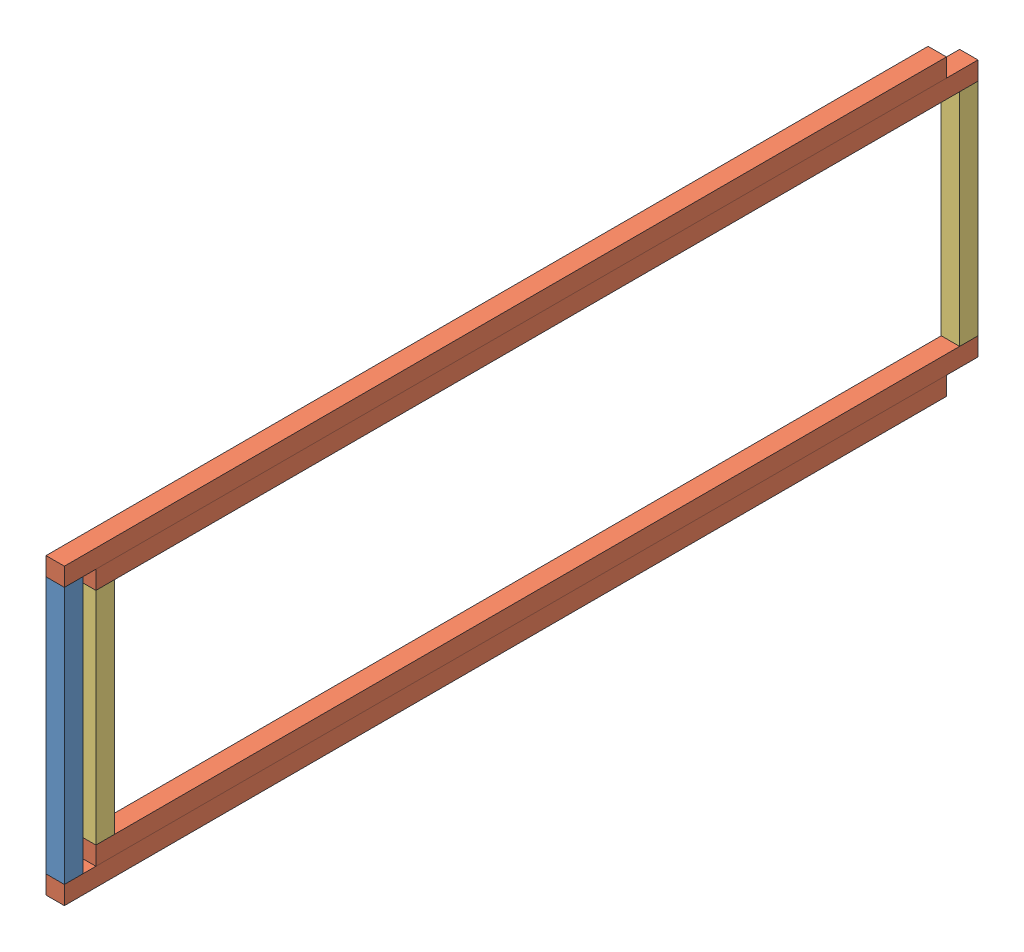
SolidWorks assembly Version 2.0 MAST, configuration Default. Lengths in mm.
Overall size (25.4 406.4 1262.78).
7 component instances, 3 part files, 17 mates.
Components (placement in the parent):
- Outisde Base-1: Outisde Base [Default] at (-217.3626 170.9905 454.9018) size (25.4 355.6 25.4)
- Outside long silder-1: Outside long silder [Default] at (-217.3626 -32.2095 -129.2982) x (1 0 0) z (0 1 0) size (25.4 1219.2 25.4)
- Outside long silder-2: Outside long silder [Default] at (-217.3626 348.7905 -129.2982) x (1 0 0) z (0 1 0) size (25.4 1219.2 25.4)
- inside Base-1: inside Base [Default] at (-217.3626 170.9905 411.3195) size (25.4 304.8 25.4)
- Outside long silder-3: Outside long silder [Default] at (-217.3626 -6.8095 -172.8805) x (1 0 0) z (0 1 0) size (25.4 1219.2 25.4)
- Outside long silder-4: Outside long silder [Default] at (-217.3626 323.3905 -172.8805) x (1 0 0) z (0 1 0) size (25.4 1219.2 25.4)
- inside Base-2: inside Base [Default] at (-217.3626 170.9905 -782.4805) size (25.4 304.8 25.4)
Mates (geometry in assembly coordinates):
- Coincident1: coincident aligned: plane of Outisde Base-1 through (-217.3626 170.9905 480.3018) normal (0 0 1); plane of Outside long silder-1 through (-230.0626 -6.8095 480.3018) normal (0 0 1)
- Coincident2: coincident aligned: plane of Outisde Base-1 through (-204.6626 -6.8095 480.3018) normal (1 0 0); plane of Outside long silder-1 through (-204.6626 -6.8095 480.3018) normal (1 0 0)
- Coincident3: coincident anti-aligned: plane of Outisde Base-1 through (-230.0626 -6.8095 480.3018) normal (0 -1 0); plane of Outside long silder-1 through (-217.3626 -6.8095 -129.2982) normal (0 1 0)
- Coincident5: coincident aligned: plane of Outisde Base-1 through (-217.3626 170.9905 480.3018) normal (0 0 1); plane of Outside long silder-2 through (-230.0626 374.1905 480.3018) normal (0 0 1)
- Coincident6: coincident aligned: plane of Outisde Base-1 through (-204.6626 -6.8095 480.3018) normal (1 0 0); plane of Outside long silder-2 through (-204.6626 374.1905 480.3018) normal (1 0 0)
- Coincident8: coincident aligned: plane of Outside long silder-2 through (-204.6626 374.1905 480.3018) normal (1 0 0); plane of inside Base-1 through (-204.6626 18.5905 436.7195) normal (1 0 0)
- Distance1: distance = 25.4 mm anti-aligned: plane of inside Base-1 through (-230.0626 18.5905 436.7195) normal (0 -1 0); plane of Outside long silder-1 through (-217.3626 -6.8095 -129.2982) normal (0 1 0)
- Coincident13: coincident aligned: plane of Outside long silder-1 through (-204.6626 -6.8095 480.3018) normal (1 0 0); plane of Outside long silder-3 through (-204.6626 18.5905 436.7195) normal (1 0 0)
- Coincident14: coincident anti-aligned: plane of Outside long silder-1 through (-217.3626 -6.8095 -129.2982) normal (0 1 0); plane of Outside long silder-3 through (-217.3626 -6.8095 -172.8805) normal (0 -1 0)
- Coincident16: coincident aligned: plane of Outside long silder-2 through (-204.6626 374.1905 480.3018) normal (1 0 0); plane of Outside long silder-4 through (-204.6626 348.7905 436.7195) normal (1 0 0)
- Coincident19: coincident anti-aligned: plane of Outside long silder-2 through (-217.3626 348.7905 -129.2982) normal (0 -1 0); plane of Outside long silder-4 through (-217.3626 348.7905 -172.8805) normal (0 1 0)
- Coincident20: coincident anti-aligned: plane of Outisde Base-1 through (-230.0626 348.7905 480.3018) normal (0 1 0); plane of Outside long silder-2 through (-217.3626 348.7905 -129.2982) normal (0 -1 0)
- Coincident21: coincident aligned: plane of inside Base-1 through (-217.3626 170.9905 436.7195) normal (0 0 1); plane of Outside long silder-4 through (-230.0626 348.7905 436.7195) normal (0 0 1)
- Coincident22: coincident aligned: plane of inside Base-1 through (-217.3626 170.9905 436.7195) normal (0 0 1); plane of Outside long silder-3 through (-230.0626 18.5905 436.7195) normal (0 0 1)
- Coincident25: coincident aligned: plane of Outside long silder-3 through (-204.6626 18.5905 436.7195) normal (1 0 0); plane of inside Base-2 through (-204.6626 18.5905 -757.0805) normal (1 0 0)
- Coincident26: coincident aligned: plane of Outside long silder-3 through (-230.0626 18.5905 -782.4805) normal (0 0 -1); plane of inside Base-2 through (-217.3626 170.9905 -782.4805) normal (0 0 -1)
- Coincident27: coincident anti-aligned: plane of Outside long silder-3 through (-217.3626 18.5905 -172.8805) normal (0 1 0); plane of inside Base-2 through (-230.0626 18.5905 -757.0805) normal (0 -1 0)
